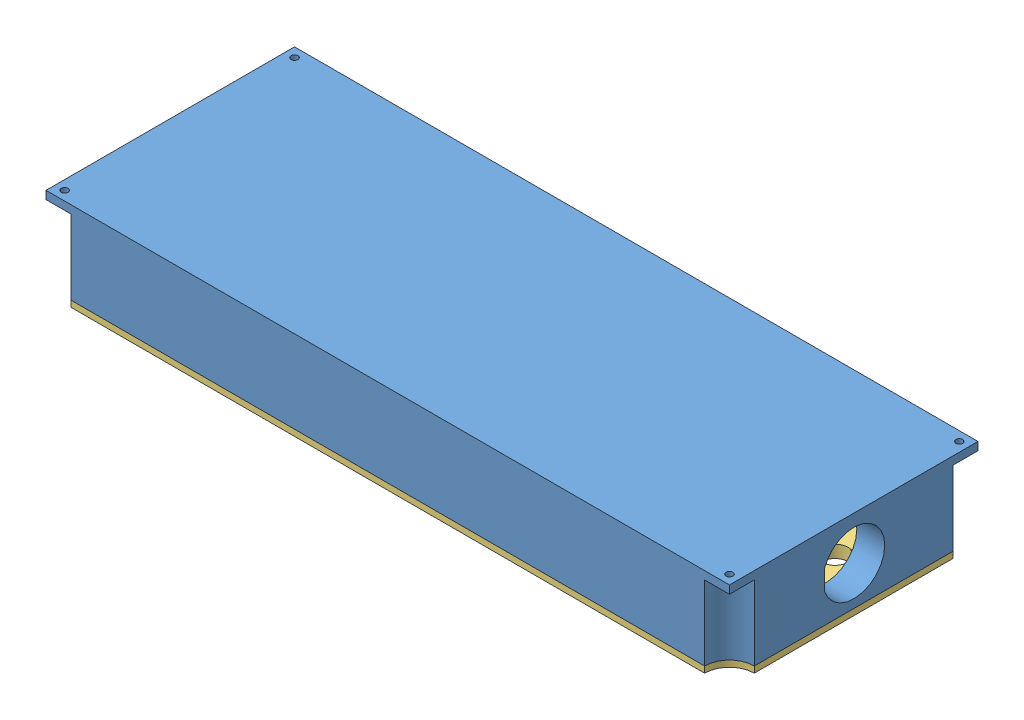
SolidWorks assembly new assembly, configuration Default. Lengths in mm.
Overall size (279.4 38.21 101.6).
3 component instances, 3 part files, 5 mates.
Components (placement in the parent):
- box1-1: box1 [Default] at origin size (279.4 33.78 101.6)
- Pcb,display,rpi-1: Pcb,display,rpi [Default] at (63.1246 143.4996 96.5223) x (-1 0 0) z (0 -1 0) size (203.2 76.2 25.48)
- Lid-1: Lid [Default] at (25.4 -36.322 0) x (1 0 0) z (0 0 -1) size (279.4 5.08 101.6)
Mates (geometry in assembly coordinates):
- Coincident1: coincident anti-aligned: plane of box1-1 through (102.87 -17.78 29.21) normal (0 -1 0); plane of Pcb,display,rpi-1 through (-0.1839 -17.78 0.1817) normal (0 1 0)
- Parallel1: parallel anti-aligned: line of box1-1 through (-102.87 -17.78 -39.37) axis (0 0 1); line of Pcb,display,rpi-1 through (101.4161 -19.38 38.2817) axis (0 0 -1)
- Coincident6: coincident anti-aligned: plane of box1-1 through (165.1 -33.782 -50.8) normal (0 -1 0); plane of Lid-1 through (25.4 -33.782 0) normal (0 1 0)
- Coincident8: coincident aligned: circle of box1-1; circle of Lid-1
- Coincident9: coincident aligned: circle of box1-1; circle of Lid-1
